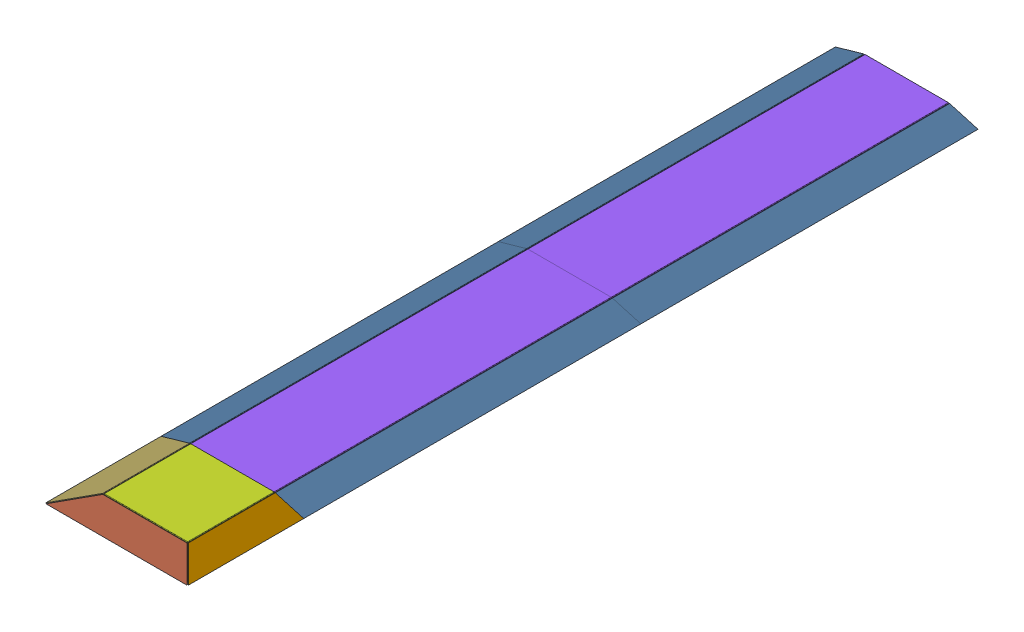
SolidWorks assembly GE-15025_ASM, configuration Default. Lengths in mm.
Overall size (859.43 57.27 4763.88).
34 component instances, 12 part files, 0 mates.
Components (placement in the parent):
- GE-15019_ASM-1: GE-15019_ASM [Default] at origin size (558.8 44.45 2032)
  - GE-15019-01-1: GE-15019-01 [Default] at origin size (558.8 12.7 2032)
  - GE-15019-02-1: GE-15019-02 [Default] at (457.2 -19.05 0) size (101.6 19.05 2032)
  - GE-15019-02-2: GE-15019-02 [Default] at (0 -19.05 0) size (101.6 19.05 2032)
  - GE-15019-02-3: GE-15019-02 [Default] at (228.6 -19.05 0) size (101.6 19.05 2032)
  - GE-15019-03-1: GE-15019-03 [Default] at (457.2 -31.75 0) size (101.6 12.7 2032)
  - GE-15019-03-2: GE-15019-03 [Default] at (228.6 -31.75 0) size (101.6 12.7 2032)
  - GE-15019-03-3: GE-15019-03 [Default] at (0 -31.75 0) size (101.6 12.7 2032)
- GE-15019_ASM-2: GE-15019_ASM [Default] at (0 0 2032) size (558.8 44.45 2032)
  - GE-15019-01-1: GE-15019-01 [Default] at origin size (558.8 12.7 2032)
  - GE-15019-02-1: GE-15019-02 [Default] at (457.2 -19.05 0) size (101.6 19.05 2032)
  - GE-15019-02-2: GE-15019-02 [Default] at (0 -19.05 0) size (101.6 19.05 2032)
  - GE-15019-02-3: GE-15019-02 [Default] at (228.6 -19.05 0) size (101.6 19.05 2032)
  - GE-15019-03-1: GE-15019-03 [Default] at (457.2 -31.75 0) size (101.6 12.7 2032)
  - GE-15019-03-2: GE-15019-03 [Default] at (228.6 -31.75 0) size (101.6 12.7 2032)
  - GE-15019-03-3: GE-15019-03 [Default] at (0 -31.75 0) size (101.6 12.7 2032)
- GE-15020_ASM-1: GE-15020_ASM [Default] at (0 0 4064) size (558.8 44.45 549.27)
  - GE-15020-01-1: GE-15020-01 [Default] at origin size (558.8 12.7 549.27)
  - GE-15020-02-1: GE-15020-02 [Default] at (457.2 -19.05 0) size (101.6 19.05 549.27)
  - GE-15020-02-2: GE-15020-02 [Default] at (0 -19.05 0) size (101.6 19.05 549.27)
  - GE-15020-02-3: GE-15020-02 [Default] at (228.6 -19.05 0) size (101.6 19.05 549.27)
  - GE-15020-03-1: GE-15020-03 [Default] at (457.2 -31.75 0) size (101.6 12.7 549.27)
  - GE-15020-03-2: GE-15020-03 [Default] at (228.6 -31.75 0) size (101.6 12.7 549.27)
  - GE-15020-03-3: GE-15020-03 [Default] at (0 -31.75 0) size (101.6 12.7 549.27)
- GE-15026-1: GE-15026 [Default] at (25.4 12.7 4064) size (508 6.35 524.55)
- GE-15027-1: GE-15027 [Default] at (25.4 12.7 2032) size (508 6.35 2032)
- GE-15027-2: GE-15027 [Default] at (25.4 12.7 0) size (508 6.35 2032)
- GE-15028-1: GE-15028 [Default] at (533.4 12.7 4064) x (0.961262 -0.275637 0) z (0 0 1) size (180.98 6.35 694.31)
- GE-15029-1: GE-15029 [Default] at (533.4 12.7 2032) x (0.961262 -0.275637 0) z (0 0 1) size (180.98 6.35 2032)
- GE-15029-2: GE-15029 [Default] at (533.4 12.7 0) x (0.961262 -0.275637 0) z (0 0 1) size (180.98 6.35 2032)
- GE-15029-3: GE-15029 [Default] at (25.4 12.7 2032) x (-0.961262 -0.275637 0) z (0 0 -1) size (180.98 6.35 2032)
- GE-15029-4: GE-15029 [Default] at (25.4 12.7 4064) x (-0.961262 -0.275637 0) z (0 0 -1) size (180.98 6.35 2032)
- GE-15030-1: GE-15030 [Default] at (-148.56 -37.1825 4761.8358) x (1 -0.000001 0.000005) z (-0.000005 -0.275637 0.961262) size (848.87 7.38 182.01)
- GE-15031-1: GE-15031 [Default] at (25.4 12.7 4064) x (-0.961262 -0.275637 0) z (0 0 -1) size (180.98 6.35 694.31)
